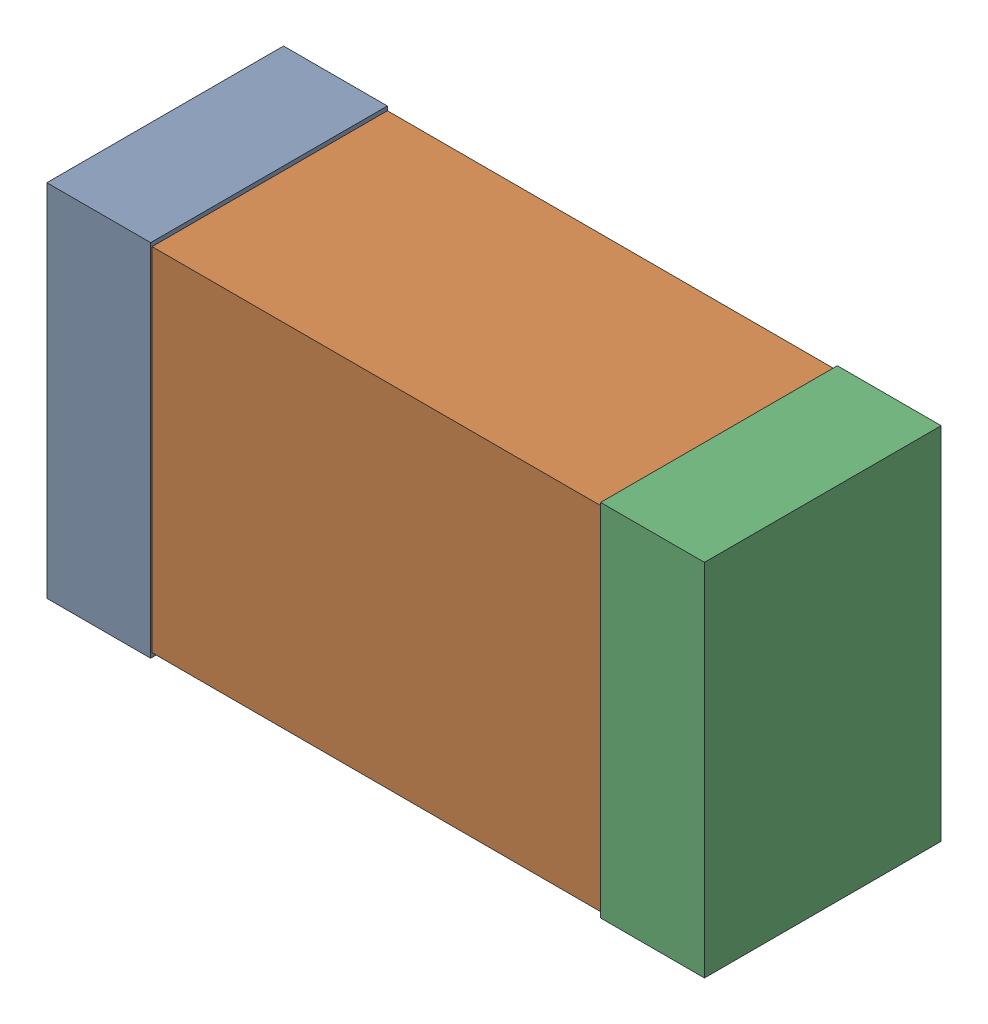
SolidWorks assembly USB23_C9, configuration Default. Lengths in mm.
Overall size (2.38 1.3 0.85).
6 component instances, 2 part files, 0 mates.
Components (placement in the parent):
- 384311232-1: 384311232 [Default] at (148.86 59.055 0) size (0.38 1.3 0.85)
  - Extruded_8-1: Extruded_8 [Default] at origin size (0.38 1.3 0.85)
- 402662800-1: 402662800 [Default] at (149.86 59.055 0) size (2.2 1.27 0.85)
  - Extruded_30-1: Extruded_30 [Default] at origin size (2.2 1.27 0.85)
- 384311232-2: 384311232 [Default] at (150.86 59.055 0) size (0.38 1.3 0.85)
  - Extruded_8-1: Extruded_8 [Default] at origin size (0.38 1.3 0.85)
